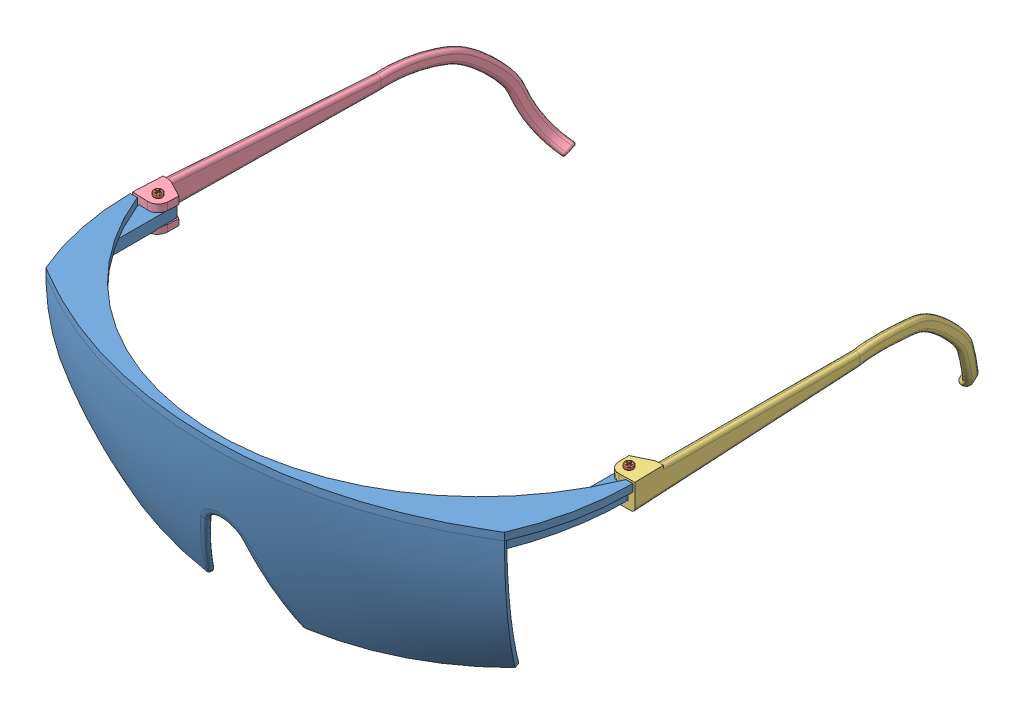
SolidWorks assembly Assembly, configuration Default. Lengths in mm.
Overall size (146.66 49.36 162.03).
5 component instances, 4 part files, 12 mates.
Components (placement in the parent):
- Lens (FINAL)-1: Lens (FINAL) [Default] at (34.7489 98.8593 130.9025) size (146.33 48.28 56.02)
- Screw-2: Screw [Default] at (-33.1799 102.0893 97.0013) x (0 -1 0) z (-0.983982 0 0.178266) size (8.8 2.43 2.43)
- Screw-3: Screw [Default] at (102.6777 102.0893 97.0013) x (0 -1 0) z (0.008078 0 0.999967) size (8.8 2.43 2.43)
- left_temple-1: left_temple [Default] at (108.1925 -24.9199 146.6645) x (0.999783 0 -0.020814) z (0.020814 0 0.999783) size (12.48 36.8 158.23)
- right_temple-4: right_temple [Default] at (-60.1105 -24.9199 145.4855) x (0.998757 0 0.049853) z (-0.049853 0 0.998757) size (12.48 36.8 111.42)
Mates (geometry in assembly coordinates):
- Concentric5: concentric: cylinder of Lens (FINAL)-1 through (-33.1799 105.5193 97.0013) axis (0 -1 0) radius 0.63; cylinder of Screw-2 through (-33.1799 102.0893 97.0013) axis (0 -1 0) radius 0.62
- Concentric11: concentric: cylinder of Lens (FINAL)-1 through (102.6777 105.5193 97.0013) axis (0 -1 0) radius 0.63; cylinder of left_temple-1 through (102.6777 101.0093 97.0013) axis (0 -1 0) radius 0.75
- Concentric13: concentric: cylinder of Screw-3 through (102.6777 102.0893 97.0013) axis (0 -1 0) radius 0.62; cylinder of left_temple-1 through (102.6777 101.0093 97.0013) axis (0 -1 0) radius 0.75
- Coincident26: coincident: plane of Lens (FINAL)-1 through (34.7489 98.8593 130.9025) normal (0 1 0); plane of left_temple-1 through (106.9437 98.8593 86.6775) normal (0 -1 0)
- Concentric14: concentric: cylinder of Screw-2 through (-33.1799 101.2382 97.0013) axis (0 -1 0) radius 0.62; cylinder of ? through (-33.1799 85.2962 97.0013) axis (0 1 0) radius 0.75
- Concentric15: concentric: cylinder of Screw-2 through (-33.1799 101.2382 97.0013) axis (0 -1 0) radius 0.62; cylinder of ? through (-33.1799 90.8595 97.0013) axis (0 -1 0) radius 0.75
- Coincident32: coincident: plane of Lens (FINAL)-1 through (-33.7299 98.8593 96.4513) normal (0 1 0); plane of ? through (-37.6599 98.8593 86.7685) normal (0 -1 0)
- Concentric16: concentric: cylinder of Screw-2 through (-33.1799 105.6624 97.0013) axis (0 -1 0) radius 0.62; cylinder of ? through (-33.1799 101.0093 97.0013) axis (0 -1 0) radius 0.75
- Concentric18: concentric: cylinder of Screw-2 through (-33.1799 102.0893 97.0013) axis (0 -1 0) radius 0.62; circle of right_temple-4
- Coincident35: coincident: circle of Screw-2; plane of right_temple-4 through (-30.3806 101.0093 100.094) normal (0 1 0)
- Coincident41: coincident: plane of Lens (FINAL)-1 through (-33.7299 98.8593 96.4513) normal (0 1 0); plane of right_temple-4 through (-37.1442 98.8593 86.5572) normal (0 -1 0)
- Coincident42: coincident: plane of Screw-3 through (103.2976 101.0093 96.9963) normal (0 -1 0); plane of left_temple-1 through (99.7897 101.0093 100.0121) normal (0 1 0)
